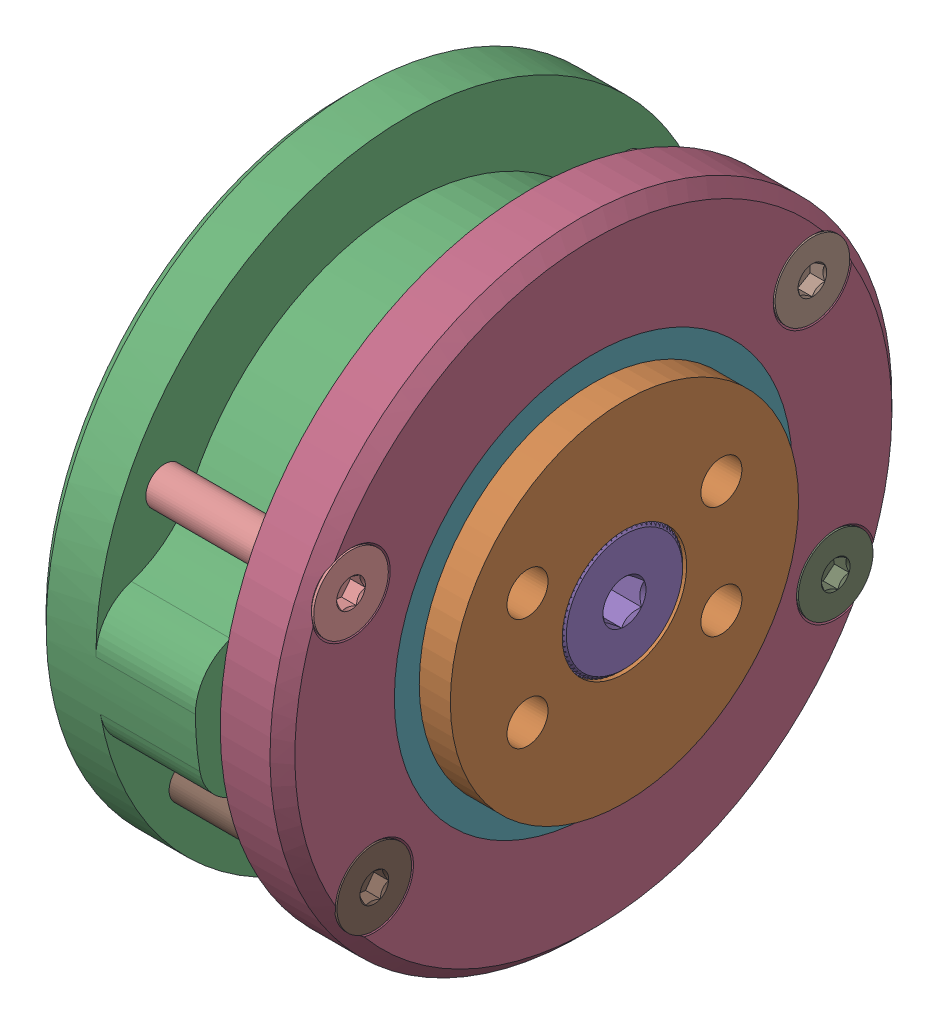
SolidWorks assembly 2808Hubmotor-assem, configuration Default. Lengths in mm.
Overall size (25.41 54.16 54.16).
11 component instances, 7 part files, 35 mates.
Components (placement in the parent):
- 2808HM-innerBase-1: 2808HM-innerBase [Default] at origin size (17.5 27.26 28)
- 2808HM-innerCap-1: 2808HM-innerCap [Default] at origin size (9.5 28 28)
- 2808HM-outerBase-1: 2808HM-outerBase [Default] x (1 0 0) z (0 -0.0871 0.9962) size (13 50 50)
- 2808HM-outerCap-1: 2808HM-outerCap [Default] x (1 0 0) z (0 -0.0871 0.9962) size (7.3 50 50)
- 6mmShaft_10mmL_ShoulderScrew-1: 6mmShaft_10mmL_ShoulderScrew [92981A100] x (0 -0.924225 -0.381849) z (1 0 0) size (10 10 25.41)
- 25mmID_32mmOD_4mmDepth_UnflangedRadialBearing-1: 25mmID_32mmOD_4mmDepth_UnflangedRadialBearing [Default] at (-8 0 0) size (4 32 32)
- 25mmID_32mmOD_4mmDepth_UnflangedRadialBearing-2: 25mmID_32mmOD_4mmDepth_UnflangedRadialBearing [Default] at (8 0 0) size (4 32 32)
- M3x0.5_20mm_FHCS-1: M3x0.5_20mm_FHCS [91294A136] at (0 12.3309 -17.6125) x (0 0 -1) z (1 0 0) size (6 6 20.12)
- M3x0.5_20mm_FHCS-2: M3x0.5_20mm_FHCS [91294A136] at (0 -9.0874 -19.4851) x (0 0.158553 -0.987351) z (1 0 0) size (6 6 20.12)
- M3x0.5_20mm_FHCS-4: M3x0.5_20mm_FHCS [91294A136] at (0 9.0874 19.4851) x (0 0.371154 -0.928571) z (1 0 0) size (6 6 20.12)
- M3x0.5_20mm_FHCS-5: M3x0.5_20mm_FHCS [91294A136] at (0 -12.3309 17.6125) x (0 0.421154 -0.906989) z (1 0 0) size (6 6 20.12)
Mates (geometry in assembly coordinates):
- Concentric1: concentric aligned: cylinder of 2808HM-innerCap-1 through (-18.538 0 0) axis (-1 0 0) radius 3; cylinder of 6mmShaft_10mmL_ShoulderScrew-1 through (-12.5 0 0) axis (-1 0 0) radius 3
- Coincident1: coincident anti-aligned: plane of 2808HM-innerCap-1 through (7.5 3 0) normal (1 0 0); plane of 6mmShaft_10mmL_ShoulderScrew-1 through (7.5 -1.9092 4.6211) normal (-1 0 0)
- Concentric2: concentric aligned: cylinder of 2808HM-innerBase-1 through (-18.538 0 0) axis (-1 0 0) radius 3; cylinder of 6mmShaft_10mmL_ShoulderScrew-1 through (-12.5 0 0) axis (-1 0 0) radius 3
- Coincident2: coincident anti-aligned: plane of 2808HM-innerBase-1 through (5 6.5 0) normal (1 0 0); plane of 2808HM-innerCap-1 through (5 2.75 -14) normal (-1 0 0)
- Coincident3: coincident anti-aligned: plane of 2808HM-innerBase-1 through (5 2.75 -14) normal (0 1 0); plane of 2808HM-innerCap-1 through (3 2.75 -14) normal (0 -1 0)
- Concentric4: concentric aligned: cylinder of 2808HM-innerBase-1 through (-18.538 0 0) axis (-1 0 0) radius 12.5; cylinder of 25mmID_32mmOD_4mmDepth_UnflangedRadialBearing-1 through (-8 0 0) axis (-1 0 0) radius 12.5
- Coincident5: coincident anti-aligned: plane of 2808HM-innerBase-1 through (-10 14 0) normal (1 0 0); plane of 25mmID_32mmOD_4mmDepth_UnflangedRadialBearing-1 through (-10 16 0) normal (-1 0 0)
- Concentric5: concentric aligned: cylinder of 2808HM-innerCap-1 through (-18.538 0 0) axis (-1 0 0) radius 12.5; cylinder of 25mmID_32mmOD_4mmDepth_UnflangedRadialBearing-2 through (8 0 0) axis (-1 0 0) radius 12.5
- Coincident6: coincident anti-aligned: plane of 2808HM-innerCap-1 through (10 12.5 0) normal (-1 0 0); plane of 25mmID_32mmOD_4mmDepth_UnflangedRadialBearing-2 through (10 16 0) normal (1 0 0)
- Concentric6: concentric aligned: cylinder of 2808HM-outerBase-1 through (-18.538 0 0) axis (-1 0 0) radius 16; cylinder of 25mmID_32mmOD_4mmDepth_UnflangedRadialBearing-1 through (-8 0 0) axis (-1 0 0) radius 16
- Coincident7: coincident anti-aligned: plane of 2808HM-outerBase-1 through (-6 15.9392 1.3936) normal (-1 0 0); plane of 25mmID_32mmOD_4mmDepth_UnflangedRadialBearing-1 through (-6 16 0) normal (1 0 0)
- Concentric8: concentric anti-aligned: cylinder of 2808HM-outerCap-1 through (-18.538 0 0) axis (-1 0 0) radius 18.7; cylinder of 2808HM-clamp-1 through (-75.7107 0 0) axis (1 0 0) radius 18.7
- Concentric10: concentric anti-aligned: cylinder of 2808HM-clamp-1 through (10 11 -19.0526) axis (1 0 0) radius 1.7; cylinder of M3x0.5_20mm_FHCS-1 through (-10 12.3309 -17.6125) axis (-1 0 0) radius 1.5
- Coincident9: coincident aligned: plane of 2808HM-clamp-1 through (10 0 0) normal (1 0 0); plane of M3x0.5_20mm_FHCS-1 through (10 12.3309 -17.6125) normal (1 0 0)
- Concentric11: concentric anti-aligned: cylinder of 2808HM-clamp-1 through (10 -11 -19.0526) axis (1 0 0) radius 1.7; cylinder of M3x0.5_20mm_FHCS-2 through (-10 -9.0874 -19.4851) axis (-1 0 0) radius 1.5
- Coincident10: coincident aligned: plane of 2808HM-clamp-1 through (10 0 0) normal (1 0 0); plane of M3x0.5_20mm_FHCS-2 through (10 -9.0874 -19.4851) normal (1 0 0)
- Concentric12: concentric anti-aligned: cylinder of 2808HM-clamp-1 through (10 22 0) axis (1 0 0) radius 1.7; cylinder of M3x0.5_20mm_FHCS-3 through (-10 22 0) axis (-1 0 0) radius 1.5
- Coincident11: coincident aligned: plane of 2808HM-clamp-1 through (10 0 0) normal (1 0 0); plane of M3x0.5_20mm_FHCS-3 through (10 22 0) normal (1 0 0)
- Concentric13: concentric anti-aligned: cylinder of 2808HM-clamp-1 through (10 11 19.0526) axis (1 0 0) radius 1.7; cylinder of M3x0.5_20mm_FHCS-4 through (-10 9.0874 19.4851) axis (-1 0 0) radius 1.5
- Coincident12: coincident aligned: plane of 2808HM-clamp-1 through (10 0 0) normal (1 0 0); plane of M3x0.5_20mm_FHCS-4 through (10 9.0874 19.4851) normal (1 0 0)
- Concentric14: concentric anti-aligned: cylinder of 2808HM-clamp-1 through (10 -11 19.0526) axis (1 0 0) radius 1.7; cylinder of M3x0.5_20mm_FHCS-5 through (-10 -12.3309 17.6125) axis (-1 0 0) radius 1.5
- Coincident13: coincident aligned: plane of 2808HM-clamp-1 through (10 0 0) normal (1 0 0); plane of M3x0.5_20mm_FHCS-5 through (10 -12.3309 17.6125) normal (1 0 0)
- Concentric15: concentric anti-aligned: cylinder of 2808HM-clamp-1 through (10 -22 0) axis (1 0 0) radius 1.7; cylinder of M3x0.5_20mm_FHCS-6 through (-10 -22 0) axis (-1 0 0) radius 1.5
- Coincident14: coincident aligned: plane of 2808HM-clamp-1 through (10 0 0) normal (1 0 0); plane of M3x0.5_20mm_FHCS-6 through (10 -22 0) normal (1 0 0)
- Concentric16: concentric aligned: cylinder of 2808HM-outerBase-1 through (-18.538 0 0) axis (-1 0 0) radius 19; cylinder of 2808HM-outerCap-1 through (-18.538 0 0) axis (-1 0 0) radius 19
- Concentric17: concentric anti-aligned: cylinder of 2808HM-outerCap-1 through (10 9.0874 19.4851) axis (1 0 0) radius 1.7; cylinder of M3x0.5_20mm_FHCS-4 through (-10 9.0874 19.4851) axis (-1 0 0) radius 1.5
- Coincident15: coincident aligned: plane of 2808HM-outerCap-1 through (10 15.9392 1.3936) normal (1 0 0); plane of M3x0.5_20mm_FHCS-4 through (10 9.0874 19.4851) normal (1 0 0)
- Concentric18: concentric aligned: cylinder of 2808HM-outerBase-1 through (-10 9.0874 19.4851) axis (-1 0 0) radius 1.25; cylinder of M3x0.5_20mm_FHCS-4 through (-10 9.0874 19.4851) axis (-1 0 0) radius 1.5
- Coincident17: coincident anti-aligned: plane of 2808HM-outerBase-1 through (3 18.9278 1.6549) normal (1 0 0); plane of 2808HM-outerCap-1 through (3 18.9278 1.6549) normal (-1 0 0)
- Concentric19: concentric anti-aligned: cylinder of 2808HM-outerCap-1 through (10 -12.3309 17.6125) axis (1 0 0) radius 1.7; cylinder of M3x0.5_20mm_FHCS-5 through (-10 -12.3309 17.6125) axis (-1 0 0) radius 1.5
- Coincident18: coincident aligned: plane of 2808HM-outerCap-1 through (10 15.9392 1.3936) normal (1 0 0); plane of M3x0.5_20mm_FHCS-5 through (10 -12.3309 17.6125) normal (1 0 0)
- Concentric20: concentric anti-aligned: cylinder of 2808HM-outerCap-1 through (10 -9.0874 -19.4851) axis (1 0 0) radius 1.7; cylinder of M3x0.5_20mm_FHCS-2 through (-10 -9.0874 -19.4851) axis (-1 0 0) radius 1.5
- Coincident19: coincident aligned: plane of 2808HM-outerCap-1 through (10 15.9392 1.3936) normal (1 0 0); plane of M3x0.5_20mm_FHCS-2 through (10 -9.0874 -19.4851) normal (1 0 0)
- Concentric21: concentric anti-aligned: cylinder of 2808HM-outerCap-1 through (10 12.3309 -17.6125) axis (1 0 0) radius 1.7; cylinder of M3x0.5_20mm_FHCS-1 through (-10 12.3309 -17.6125) axis (-1 0 0) radius 1.5
- Coincident20: coincident aligned: plane of 2808HM-outerCap-1 through (10 15.9392 1.3936) normal (1 0 0); plane of M3x0.5_20mm_FHCS-1 through (10 12.3309 -17.6125) normal (1 0 0)
